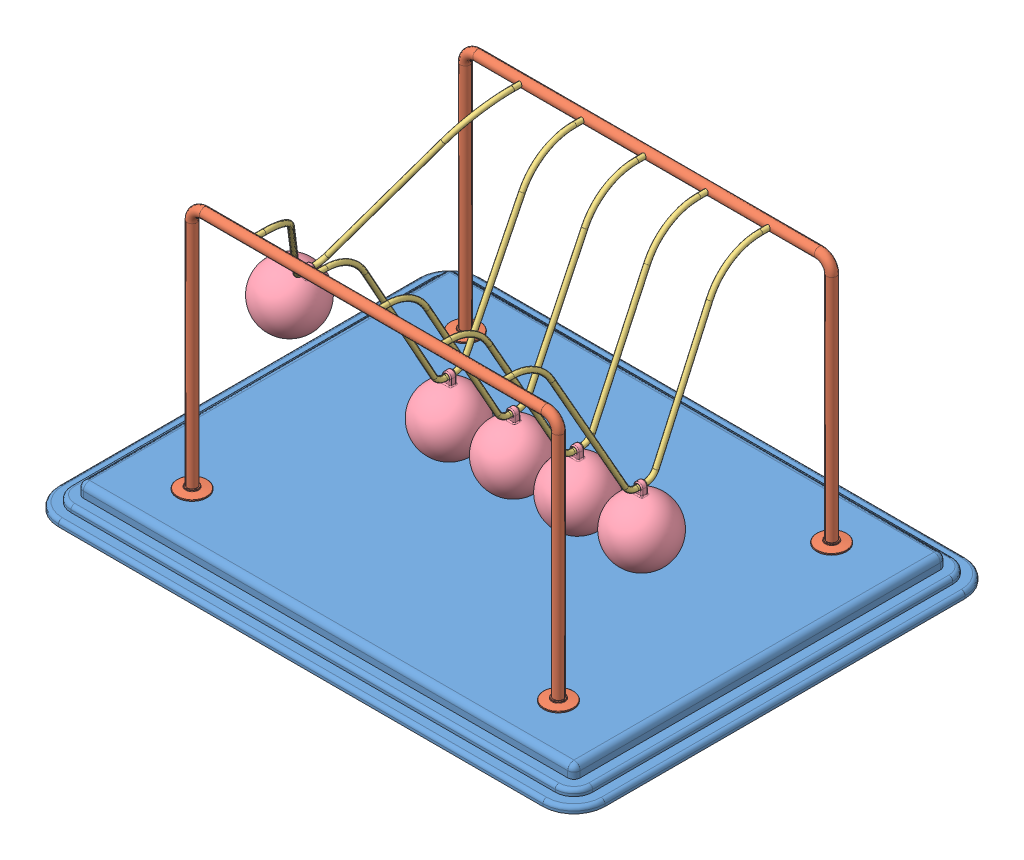
SolidWorks assembly Newtons Cradle NewtonsCradle 0231, configuration Default. Lengths in mm.
Overall size (440 222 340).
13 component instances, 4 part files, 34 mates.
Components (placement in the parent):
- Base NewtonsCradle 0231-1: Base NewtonsCradle 0231 [Default] at (-16.2968 -4.1587 11.425) size (440 20 340)
- frame NewtonsCradle 0231-1: frame NewtonsCradle 0231 [Default] at (-16.2968 144.4547 -98.575) size (319 202 24)
- frame NewtonsCradle 0231-2: frame NewtonsCradle 0231 [Default] at (-16.2968 144.4547 121.425) x (-1 0 0) z (0 0 -1) size (319 202 24)
- Hanging thing NewtonsCradle 0231-1: Hanging thing NewtonsCradle 0231 [Default] at (-157.6326 134.1825 11.425) x (0 0 1) z (-0.859985 0.510319 0) size (220 129 4)
- Hanging thing NewtonsCradle 0231-2: Hanging thing NewtonsCradle 0231 [Default] at (-66.576 122.8418 11.425) x (0 0 1) z (-0.999994 0.003446 0) size (220 129 4)
- Hanging thing NewtonsCradle 0231-3: Hanging thing NewtonsCradle 0231 [Default] at (-15.6923 122.8436 11.425) x (0 0 1) z (-0.999972 -0.007464 0) size (220 129 4)
- Hanging thing NewtonsCradle 0231-4: Hanging thing NewtonsCradle 0231 [Default] at (35.2213 122.8555 11.425) x (0 0 1) z (-0.999824 -0.018742 0) size (220 129 4)
- Hanging thing NewtonsCradle 0231-5: Hanging thing NewtonsCradle 0231 [Default] at (86.0287 122.8747 11.425) x (0 0 1) z (-0.999588 -0.028711 0) size (220 129 4)
- Sphere NewtonsCradle 0231-1: Sphere NewtonsCradle 0231 [Default] at (-195.3962 70.5436 11.425) x (0.859985 -0.510319 0) z (0 0 1) size (50 58.5 50)
- Sphere NewtonsCradle 0231-2: Sphere NewtonsCradle 0231 [Default] at (88.1533 48.9052 11.425) x (0.999588 0.028711 0) z (0 0 1) size (50 58.5 50)
- Sphere NewtonsCradle 0231-3: Sphere NewtonsCradle 0231 [Default] at (-15.14 48.8456 11.425) x (0.999972 0.007464 0) z (0 0 1) size (50 58.5 50)
- Sphere NewtonsCradle 0231-4: Sphere NewtonsCradle 0231 [Default] at (36.6081 48.8685 11.425) x (0.999824 0.018742 0) z (0 0 1) size (50 58.5 50)
- Sphere NewtonsCradle 0231-5: Sphere NewtonsCradle 0231 [Default] at (-66.831 48.8422 11.425) x (0.999994 -0.003446 0) z (0 0 1) size (50 58.5 50)
Mates (geometry in assembly coordinates):
- Coincident1: coincident anti-aligned: plane of Base-1 through (-211.2968 5.8413 156.425) normal (0 1 0); plane of frame-2 through (-175.7968 5.8413 121.425) normal (0 -1 0)
- Coincident2: coincident anti-aligned: plane of Base-1 through (-211.2968 5.8413 156.425) normal (0 1 0); plane of frame-1 through (143.2032 5.8413 -98.575) normal (0 -1 0)
- Concentric1: concentric anti-aligned: cylinder of frame-1 through (-116.2968 203.8413 -94.575) axis (0 0 -1) radius 2; cylinder of frame-2 through (-116.2968 203.8413 117.425) axis (0 0 1) radius 2
- Concentric2: concentric anti-aligned: cylinder of frame-1 through (83.7032 203.8413 -94.575) axis (0 0 -1) radius 2; cylinder of frame-2 through (83.7032 203.8413 117.425) axis (0 0 1) radius 2
- Distance1: distance = 60 mm: plane of frame-1 through (-16.2968 144.4547 -98.575) normal (0 0 1); line of Base-1 through (-211.2968 -12.1587 -158.575) axis (1 0 0)
- Distance2: distance = 60 mm: line of Base-1 through (178.7032 -12.1587 181.425) axis (-1 0 0); plane of frame-2 through (-16.2968 144.4547 121.425) normal (0 0 -1)
- Distance3: distance = 220 mm: plane of frame-2 through (-16.2968 144.4547 121.425) normal (-1 0 0); line of Base-1 through (-236.2968 -12.1587 156.425) axis (0 0 -1)
- Concentric3: concentric anti-aligned: cylinder of frame-1 through (-116.2968 203.8413 -94.575) axis (0 0 -1) radius 2; cylinder of Hanging thing-1 through (-116.2968 203.8413 111.425) axis (0 0 1) radius 2
- Concentric4: concentric anti-aligned: cylinder of frame-1 through (-116.2968 203.8413 -94.575) axis (0 0 -1) radius 2; cylinder of Hanging thing-1 through (-116.2968 203.8413 -98.575) axis (0 0 1) radius 2
- Concentric5: concentric aligned: cylinder of frame-2 through (-66.2968 203.8413 117.425) axis (0 0 1) radius 2; cylinder of Hanging thing-2 through (-66.2968 203.8413 111.425) axis (0 0 1) radius 2
- Concentric6: concentric aligned: cylinder of frame-2 through (-16.2968 203.8413 117.425) axis (0 0 1) radius 2; cylinder of Hanging thing-3 through (-16.2968 203.8413 111.425) axis (0 0 1) radius 2
- Concentric7: concentric aligned: cylinder of frame-2 through (33.7032 203.8413 117.425) axis (0 0 1) radius 2; cylinder of Hanging thing-4 through (33.7032 203.8413 111.425) axis (0 0 1) radius 2
- Concentric8: concentric aligned: cylinder of frame-2 through (83.7032 203.8413 117.425) axis (0 0 1) radius 2; cylinder of Hanging thing-5 through (83.7032 203.8413 111.425) axis (0 0 1) radius 2
- Coincident5: coincident anti-aligned: plane of frame-2 through (83.7032 203.8413 121.425) normal (0 0 -1); plane of Hanging thing-5 through (83.7032 203.8413 121.425) normal (0 0 1)
- Coincident6: coincident anti-aligned: plane of frame-2 through (33.7032 203.8413 121.425) normal (0 0 -1); plane of Hanging thing-4 through (33.7032 203.8413 121.425) normal (0 0 1)
- Coincident7: coincident anti-aligned: plane of frame-2 through (-16.2968 203.8413 121.425) normal (0 0 -1); plane of Hanging thing-3 through (-16.2968 203.8413 121.425) normal (0 0 1)
- Coincident8: coincident anti-aligned: plane of frame-2 through (-66.2968 203.8413 121.425) normal (0 0 -1); plane of Hanging thing-2 through (-66.2968 203.8413 121.425) normal (0 0 1)
- Coincident9: coincident anti-aligned: plane of frame-2 through (-116.2968 203.8413 121.425) normal (0 0 -1); plane of Hanging thing-1 through (-116.2968 203.8413 121.425) normal (0 0 1)
- Concentric9: concentric anti-aligned: cylinder of Hanging thing-1 through (-117.0163 78.8434 7.925) axis (0 0 1) radius 2; cylinder of Sphere-1 through (-117.0163 78.8434 13.925) axis (0 0 -1) radius 2
- Concentric13: concentric anti-aligned: cylinder of Hanging thing-2 through (-66.7276 78.842 7.925) axis (0 0 1) radius 2; cylinder of Sphere-5 through (-66.7276 78.842 13.925) axis (0 0 -1) radius 2
- Concentric15: concentric anti-aligned: cylinder of Hanging thing-3 through (-15.3639 78.8448 7.925) axis (0 0 1) radius 2; cylinder of Sphere-3 through (-15.3639 78.8448 13.925) axis (0 0 -1) radius 2
- Concentric16: concentric anti-aligned: cylinder of Hanging thing-5 through (87.292 78.8928 7.925) axis (0 0 1) radius 2; cylinder of Sphere-2 through (87.292 78.8928 13.925) axis (0 0 -1) radius 2
- Concentric17: concentric anti-aligned: cylinder of Hanging thing-4 through (36.0459 78.8632 7.925) axis (0 0 1) radius 2; cylinder of Sphere-4 through (36.0459 78.8632 13.925) axis (0 0 -1) radius 2
- Parallel1: parallel anti-aligned: plane of Hanging thing-1; plane of Sphere-1
- Coincident22: coincident anti-aligned: plane of Hanging thing-1; plane of Sphere-1
- Coincident12: coincident aligned: plane of Hanging thing-2 through (-66.576 122.8418 11.425) normal (0 0 1); plane of Sphere-5 through (-66.831 48.8422 11.425) normal (0 0 1)
- Coincident10: coincident aligned: plane of Hanging thing-1 through (-116.763 122.8426 11.425) normal (0 0 1); plane of Sphere-1 through (-118.5806 48.8842 11.425) normal (0 0 1)
- Coincident13: coincident anti-aligned: plane of Hanging thing-2 through (-66.576 122.8418 11.425) normal (-0.999994 0.003446 0); plane of Sphere-5 through (-66.831 48.8422 11.425) normal (0.999994 -0.003446 0)
- Coincident14: coincident anti-aligned: plane of Hanging thing-3 through (-15.6923 122.8436 11.425) normal (-0.999972 -0.007464 0); plane of Sphere-3 through (-15.14 48.8456 11.425) normal (0.999972 0.007464 0)
- Coincident15: coincident aligned: plane of Hanging thing-3 through (-15.6923 122.8436 11.425) normal (0 0 1); plane of Sphere-3 through (-15.14 48.8456 11.425) normal (0 0 1)
- Coincident18: coincident aligned: plane of Hanging thing-4 through (35.2213 122.8555 11.425) normal (0 0 1); plane of Sphere-4 through (36.6081 48.8685 11.425) normal (0 0 1)
- Coincident19: coincident anti-aligned: plane of Hanging thing-4 through (35.2213 122.8555 11.425) normal (-0.999824 -0.018742 0); plane of Sphere-4 through (36.6081 48.8685 11.425) normal (0.999824 0.018742 0)
- Coincident20: coincident anti-aligned: plane of Hanging thing-5 through (86.0287 122.8747 11.425) normal (-0.999588 -0.028711 0); plane of Sphere-2 through (88.1533 48.9052 11.425) normal (0.999588 0.028711 0)
- Coincident21: coincident aligned: plane of Hanging thing-5 through (86.0287 122.8747 11.425) normal (0 0 1); plane of Sphere-2 through (88.1533 48.9052 11.425) normal (0 0 1)
